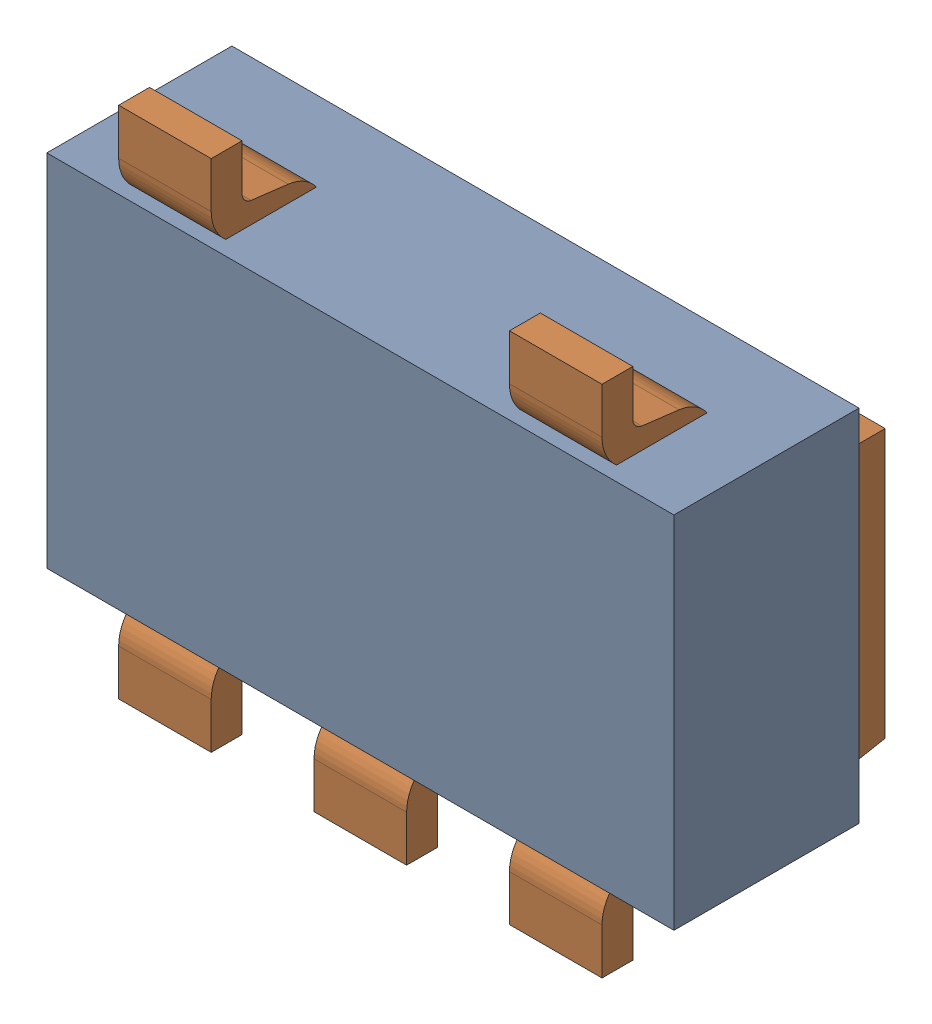
SolidWorks assembly U6, configuration Default. Lengths in mm.
Overall size (3.05 2.5 1.1).
3 component instances, 2 part files, 0 mates.
Components (placement in the parent):
- 1737248192-1: 1737248192 [Default] at (10.275 26.075 -2.544) size (3.05 1.75 0.9)
  - Extruded-19-1: Extruded-19 [Default] at origin size (3.05 1.75 0.9)
- SOT23-5L-1: SOT23-5L [Default] at (10.2749 26.0751 -2.194) x (-1 0 0) z (0 -1 0) size (3 1.1 2.5)
